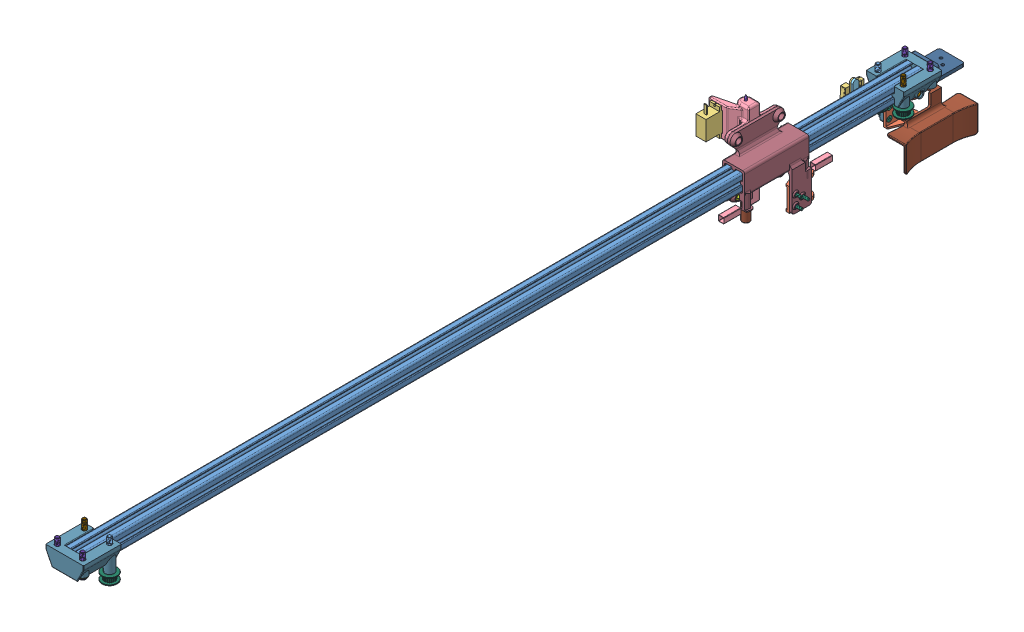
SolidWorks assembly Carriage, configuration Default. Lengths in mm.
Overall size (109.07 129.45 1054.45).
58 component instances, 29 part files, 90 mates.
Components (placement in the parent):
- 5537T237_T-Slotted Framing-1: 5537T237_T-Slotted Framing [5537T237] at origin size (19.99 19.99 1000.12)
- PenHolder-1: PenHolder [Default] at (-13.302 -1.1391 -322.9776) x (0 0 1) z (1 0 0) size (64.55 129.45 48.11)
  - Servo Lever-1: Servo Lever [Default] at (-0.5 -33.948 -30.734) x (0 -0.984808 -0.173648) z (0 -0.173648 0.984808) size (7.3 5 34)
  - SG90 Servo-1: SG90 Servo [Default] at (9.8 -28.448 -30.734) x (0 1 0) z (0 0 1) size (37.7 30.3 12)
  - PenHolder-1: PenHolder [Default] at origin size (63.5 101.91 40.64)
  - Assembly Ink Cartridge Pilot G2-1: Assembly Ink Cartridge Pilot G2 [Default] at (-23.3837 82.6746 -54.1169) x (1 0 0) z (0 -1 0) size (8.33 8.33 120.93)
    - Ink Container Tube-2: Ink Container Tube [Default] at (23.3837 43.9569 29.8776) x (-1 0 0) z (0 1 0) size (6.2 88 6)
    - Ink Container Back Plug-1: Ink Container Back Plug [Default] at (23.3837 43.9569 29.8776) x (1 0 0) z (0 1 0) size (6 4.9 6)
    - Pen Tip Holder-1: Pen Tip Holder [Default] at (23.3837 43.9569 117.8776) x (0.558829 -0.829283 0) z (0.829283 0.558829 0) size (6 18.11 6)
    - Pen Tip-1: Pen Tip [Default] at (23.3837 43.9569 135.6644) x (0.943336 0.33184 0) z (-0.33184 0.943336 0) size (2.59 15.69 2.63)
    - Roller Ball-2: Roller Ball [Default] at (23.3837 43.9569 138.8644) x (0.307657 -0.299861 -0.903012) z (0.951494 0.099481 0.29114) size (0.5 0.5 0.5)
    - Spring-3: Spring [Write] at (23.3837 43.9569 20.2276) x (1 0 0) z (0 -1 0) size (7.26 11.16 7.26)
  - Spring Cap-1: Spring Cap [Default] at (0 19.5395 -10.16) x (0.422618 0 0.906308) z (-0.906308 0 0.422618) size (8.89 53.34 10.92)
  - Pen Lifter-1: Pen Lifter [Default] at (0 -47.625 -10.16) x (-1 0 0) z (0 0 -1) size (8.89 15.4 11.43)
- CarriageSlide2-1: CarriageSlide2 [Default] at (0 0 -322.9776) x (0 1 0) z (0 0 1) size (91.53 37.4 76.2)
- GantryMount-1: GantryMount [Default] at (0 9.8114 -487.5625) x (1 0 0) z (0 0 -1) size (47.54 60.96 45)
- GT2_T2_Pulley_dzino-1: GT2_T2_Pulley_dzino [Výchozí] at (-15 -18.8236 -471.5625) x (-1 0 0) z (0 0 1) size (18 8.5 18)
- GT2_T2_Pulley_dzino-2: GT2_T2_Pulley_dzino [Výchozí] at (15 -10.8236 -471.5625) x (-1 0 0) z (0 0 1) size (18 8.5 18)
- 98269A440_Black-Oxide 18-8 Stainless Steel Washer-1: 98269A440_Black-Oxide 18-8 Stainless Steel Washer [98269A440] at (15 -6.0636 -503.5625) x (0 0 -1) z (0 -1 0) size (10 10 1.1)
- 97763A433_18-8 Stainless Steel Button Head Hex Drive Screws-1: 97763A433_18-8 Stainless Steel Button Head Hex Drive Screws [97763A433] at (15 -9.9136 -503.5625) x (-0.234384 0 -0.972144) z (0 -1 0) size (9.5 9.5 28.3)
- 91239A240_Button Head Hex Drive Screw-1: 91239A240_Button Head Hex Drive Screw [91239A240] at (15 -0.6986 -471.5625) x (0 0 -1) z (0 -1 0) size (9.5 9.5 43.34)
- 98269A440_Black-Oxide 18-8 Stainless Steel Washer-3: 98269A440_Black-Oxide 18-8 Stainless Steel Washer [98269A440] at (-15 -7.1636 -503.5625) x (-0.383049 0 0.923728) z (0 1 0) size (10 10 1.1)
- 97763A433_18-8 Stainless Steel Button Head Hex Drive Screws-2: 97763A433_18-8 Stainless Steel Button Head Hex Drive Screws [97763A433] at (-15 -9.9136 -503.5625) x (-0.129266 0 -0.99161) z (0 -1 0) size (9.5 9.5 28.3)
- 91239A244_Button Head Hex Drive Screw-2: 91239A244_Button Head Hex Drive Screw [91239A244] at (-15 -6.1986 -471.5625) x (0 0 -1) z (0 -1 0) size (9.5 9.5 48.37)
- CableChainEnd-1: CableChainEnd [Default] at (-11.44 -41.1486 -507.5595) x (0 0 1) z (0 1 0) size (33 14.5 27.6)
- 97763A433_18-8 Stainless Steel Button Head Hex Drive Screws-3: 97763A433_18-8 Stainless Steel Button Head Hex Drive Screws [97763A433] at (15 -9.9136 503.5625) x (0.234384 0 -0.972144) z (0 -1 0) size (9.5 9.5 28.3)
- 98269A440_Black-Oxide 18-8 Stainless Steel Washer-4: 98269A440_Black-Oxide 18-8 Stainless Steel Washer [98269A440] at (15 -6.0636 503.5625) x (0 0 -1) z (0 -1 0) size (10 10 1.1)
- 97763A433_18-8 Stainless Steel Button Head Hex Drive Screws-4: 97763A433_18-8 Stainless Steel Button Head Hex Drive Screws [97763A433] at (-15 -9.9136 503.5625) x (0.129266 0 -0.99161) z (0 -1 0) size (9.5 9.5 28.3)
- 98269A440_Black-Oxide 18-8 Stainless Steel Washer-5: 98269A440_Black-Oxide 18-8 Stainless Steel Washer [98269A440] at (-15 -7.1636 503.5625) x (0.383049 0 0.923728) z (0 1 0) size (10 10 1.1)
- GantryMount-3: GantryMount [NoCableCarrier] at (0 9.8114 487.5625) x (-1 0 0) z (0 0 1) size (45 28.63 45)
- CableChainEnd-2: CableChainEnd [Default] at (6.052 -42.484 -363.9276) x (0 0 1) z (0 -1 0) size (33 14.5 27.6)
- LimitSwitch-1: LimitSwitch [Default] at (-14.5667 5.08 -440.6225) x (0 1 0) z (1 0 0) size (26.78 26.12 9.4)
- BeltClip-1: BeltClip [Default] at (-11.6655 -23.2269 -377.4276) size (6.6 6.6 20)
- BeltClip-2: BeltClip [Default] at (11.6655 -23.2269 -377.4276) x (-1 0 0) z (0 0 -1) size (6.6 6.6 20)
- BeltClip-5: BeltClip [Default] at (11.6655 -23.2269 -268.5276) x (-1 0 0) z (0 0 -1) size (6.6 6.6 20)
- BeltClip-6: BeltClip [Default] at (-11.6655 -23.2269 -268.5276) size (6.6 6.6 20)
- SwitchMount-1: SwitchMount [Default] at (-8.1915 0 -451.0925) x (-1 0 0) z (0 0 1) size (12.06 26.78 27.94)
- GT2_T2_Pulley_dzino-7: GT2_T2_Pulley_dzino [Výchozí] at (-15 -10.8236 471.5625) x (-1 0 0) z (0 0 1) size (18 8.5 18)
- GT2_T2_Pulley_dzino-8: GT2_T2_Pulley_dzino [Výchozí] at (15 -18.8236 471.5625) x (-1 0 0) z (0 0 1) size (18 8.5 18)
- 91239A244_Button Head Hex Drive Screw-3: 91239A244_Button Head Hex Drive Screw [91239A244] at (15 -6.1986 471.5625) x (0 0 -1) z (0 -1 0) size (9.5 9.5 48.37)
- 91239A240_Button Head Hex Drive Screw-2: 91239A240_Button Head Hex Drive Screw [91239A240] at (-15 -0.6986 471.5625) x (0 0 -1) z (0 -1 0) size (9.5 9.5 43.34)
- 91294A133_Black-Oxide Alloy Steel Hex Drive Flat Head Screw-1: 91294A133_Black-Oxide Alloy Steel Hex Drive Flat Head Screw [91294A133] at (-15.64 -47.1486 -485.8095) x (0 0 -1) z (1 0 0) size (6 6 14.33)
- 91294A133_Black-Oxide Alloy Steel Hex Drive Flat Head Screw-2: 91294A133_Black-Oxide Alloy Steel Hex Drive Flat Head Screw [91294A133] at (-15.64 -41.1486 -493.8095) x (0 0 -1) z (1 0 0) size (6 6 14.33)
- 91294A133_Black-Oxide Alloy Steel Hex Drive Flat Head Screw-3: 91294A133_Black-Oxide Alloy Steel Hex Drive Flat Head Screw [91294A133] at (-15.64 -35.1486 -485.8095) x (0 0 -1) z (1 0 0) size (6 6 14.33)
- 91294A133_Black-Oxide Alloy Steel Hex Drive Flat Head Screw-4: 91294A133_Black-Oxide Alloy Steel Hex Drive Flat Head Screw [91294A133] at (10.252 -48.484 -342.1776) x (0 0 1) z (-1 0 0) size (6 6 14.33)
- 91294A133_Black-Oxide Alloy Steel Hex Drive Flat Head Screw-5: 91294A133_Black-Oxide Alloy Steel Hex Drive Flat Head Screw [91294A133] at (10.252 -42.484 -350.1776) x (0 0 1) z (-1 0 0) size (6 6 14.33)
- 91294A133_Black-Oxide Alloy Steel Hex Drive Flat Head Screw-6: 91294A133_Black-Oxide Alloy Steel Hex Drive Flat Head Screw [91294A133] at (10.252 -36.484 -342.1776) x (0 0 1) z (-1 0 0) size (6 6 14.33)
- 10-24 Insert-1: 10-24 Insert [Default] at (-9.558 -28.575 -297.5776) x (0 -0.924225 -0.381849) z (-1 0 0) size (7.5 7.5 5.71)
- M3 Threaded Insert-1: M3 Threaded Insert [Default] at (16.167 -48.484 -342.1776) x (0 0 1) z (-1 0 0) size (4.15 4.15 3.16)
- M3 Threaded Insert-2: M3 Threaded Insert [Default] at (-23.46 -47.1486 -485.8095) x (0 0 1) z (-1 0 0) size (4.15 4.15 3.16)
- M5 Threaded Insert-1: M5 Threaded Insert [Default] at (8.89 4.7314 -507.0625) size (6.3 6.3 6)
- M5 Threaded Insert-2: M5 Threaded Insert [Default] at (-8.89 4.7314 -507.0625) size (6.3 6.3 6)
- M5 Threaded Insert-3: M5 Threaded Insert [Default] at (14.3716 -5.6858 -487.5625) x (0 0.398395 0.917214) z (-1 0 0) size (6.3 6.3 6)
- ChainMount-1: ChainMount [Default] at (0 4.7314 -510.0625) x (1 0 0) z (0 0 -1) size (30.16 18.54 34.29)
- M3 Threaded Insert-3: M3 Threaded Insert [Default] at (-3.6513 -6.7546 -523.1125) x (0 0 1) z (0 1 0) size (4.15 4.15 3.16)
- M3 Threaded Insert-4: M3 Threaded Insert [Default] at (-3.6513 -6.7546 -535.1125) x (0 0 1) z (0 1 0) size (4.15 4.15 3.16)
- M3 Threaded Insert-5: M3 Threaded Insert [Default] at (4.3487 -6.7546 -529.1125) x (0 0 1) z (0 1 0) size (4.15 4.15 3.16)
- CarrierSupport-1: CarrierSupport [Default] at (15 -6.0636 -487.5625) x (1 0 0) z (0 0 -1) size (37.26 49.14 86.36)
Mates (geometry in assembly coordinates):
- Coincident1: coordinate: point of 5537T237_T-Slotted Framing-1
- Coincident63: coincident anti-aligned: plane of CarriageSlide2-1 through (0 0 -322.9776) normal (-1 0 0)
- Coincident64: coincident aligned: plane of CarriageSlide2-1 through (0 0 -322.9776) normal (0 1 0)
- Concentric25: concentric anti-aligned: cylinder of PenHolder-1/PenHolder-1 through (-17.5362 28.575 -348.3776) axis (1 0 0) radius 2.54; cone of CarriageSlide2-1 through (-6.317 28.575 -348.3776) axis (-1 0 0)
- Coincident65: coincident anti-aligned: plane of PenHolder-1/PenHolder-1 through (-13.302 -51.9391 -329.9626) normal (1 0 0); plane of CarriageSlide2-1 through (-13.302 -13.302 -284.8776) normal (-1 0 0)
- Coincident66: coincident anti-aligned: plane of 5537T237_T-Slotted Framing-1 through (-1.1334 6.6251 -500.0625) normal (0 0 -1); plane of GantryMount-1 through (8.1516 7.8614 -500.0625) normal (0 0 1)
- Concentric8: concentric anti-aligned: cylinder of GantryMount-1 through (-15 9.8114 -471.5625) axis (0 -1 0) radius 2.754; cylinder of GT2_T2_Pulley_dzino-1 through (-15 -18.8236 -471.5625) axis (0 1 0) radius 4
- Coincident42: coincident anti-aligned: plane of GantryMount-1 through (15 -10.8236 -471.5625) normal (0 -1 0); plane of GT2_T2_Pulley_dzino-2 through (10.5 -10.8236 -471.5625) normal (0 1 0)
- Concentric9: concentric anti-aligned: cylinder of GantryMount-1 through (15 9.8114 -471.5625) axis (0 -1 0) radius 2.754; cylinder of GT2_T2_Pulley_dzino-2 through (15 -10.8236 -471.5625) axis (0 1 0) radius 4
- Coincident46: coincident anti-aligned: plane of GantryMount-1 through (15 -6.0636 -503.5625) normal (0 -1 0); plane of 98269A440_Black-Oxide 18-8 Stainless Steel Washer-1 through (15 -6.0636 -503.5625) normal (0 1 0)
- Concentric12: concentric aligned: cylinder of GantryMount-1 through (15 -6.0636 -503.5625) axis (0 1 0) radius 5.3975; cylinder of 98269A440_Black-Oxide 18-8 Stainless Steel Washer-1 through (15 -7.1636 -503.5625) axis (0 1 0) radius 5
- Concentric26: concentric aligned: cylinder of GantryMount-1 through (15 9.8114 -503.5625) axis (0 -1 0) radius 2.754; cylinder of 97763A433_18-8 Stainless Steel Button Head Hex Drive Screws-1 through (15 -9.9136 -503.5625) axis (0 -1 0) radius 4.75
- Concentric27: concentric aligned: cylinder of GantryMount-1 through (15 9.8114 -471.5625) axis (0 -1 0) radius 2.754; cylinder of 91239A240_Button Head Hex Drive Screw-1 through (15 -22.0736 -471.5625) axis (0 -1 0) radius 4.75
- Coincident52: coincident anti-aligned: plane of GantryMount-1 through (-15 -6.0636 -503.5625) normal (0 -1 0); plane of 98269A440_Black-Oxide 18-8 Stainless Steel Washer-3 through (-15 -6.0636 -503.5625) normal (0 1 0)
- Concentric182: concentric aligned: cylinder of GantryMount-1 through (-15 9.8114 -471.5625) axis (0 -1 0) radius 2.754; cylinder of 91239A244_Button Head Hex Drive Screw-2 through (-15 -30.0736 -471.5625) axis (0 -1 0) radius 4.75
- Coincident68: coincident anti-aligned: plane of GantryMount-1 through (-18.69 9.8114 -487.5625) normal (1 0 0); plane of CableChainEnd-1 through (-18.69 -27.3486 -507.5595) normal (-1 0 0)
- Concentric183: concentric anti-aligned: cylinder of GantryMount-1 through (22.5 -47.1486 -485.8095) axis (-1 0 0) radius 1.7; cylinder of CableChainEnd-1 through (-15.69 -47.1486 -485.8095) axis (1 0 0) radius 1.7
- Parallel5: parallel aligned: plane of GantryMount-1 through (-18.69 -51.1486 -481.5725) normal (0 -1 0); plane of CableChainEnd-1 through (-11.44 -54.9486 -507.5595) normal (0 -1 0)
- Coincident71: coincident anti-aligned: plane of GT2_T2_Pulley_dzino-1 through (-15 -27.3236 -471.5625) normal (0 -1 0); plane of 91239A244_Button Head Hex Drive Screw-2 through (-19.75 -27.3236 -471.5625) normal (0 1 0)
- Coincident72: coincident anti-aligned: plane of GT2_T2_Pulley_dzino-2 through (15 -19.3236 -471.5625) normal (0 -1 0); plane of 91239A240_Button Head Hex Drive Screw-1 through (15 -19.3236 -476.3125) normal (0 1 0)
- Coincident74: coincident anti-aligned: plane of 98269A440_Black-Oxide 18-8 Stainless Steel Washer-1 through (15 -7.1636 -503.5625) normal (0 -1 0); plane of 97763A433_18-8 Stainless Steel Button Head Hex Drive Screws-1 through (10.3823 -7.1636 -502.4492) normal (0 1 0)
- Coincident53: coincident anti-aligned: plane of 98269A440_Black-Oxide 18-8 Stainless Steel Washer-3 through (-15 -7.1636 -503.5625) normal (0 -1 0); plane of 97763A433_18-8 Stainless Steel Button Head Hex Drive Screws-2 through (-19.7101 -7.1636 -502.9485) normal (0 1 0)
- Concentric184: concentric aligned: cylinder of GantryMount-1 through (-15 9.8114 -503.5625) axis (0 -1 0) radius 2.754; cylinder of 98269A440_Black-Oxide 18-8 Stainless Steel Washer-3 through (-15 -6.0636 -503.5625) axis (0 -1 0) radius 5
- Concentric185: concentric aligned: cylinder of GantryMount-1 through (-15 9.8114 -503.5625) axis (0 -1 0) radius 2.754; cylinder of 97763A433_18-8 Stainless Steel Button Head Hex Drive Screws-2 through (-15 -9.9136 -503.5625) axis (0 -1 0) radius 4.75
- Parallel6: parallel aligned: plane of 5537T237_T-Slotted Framing-1 through (-7.9883 -9.9949 500.0625) normal (0 -1 0); plane of GantryMount-1 through (15 -10.1886 -510.0625) normal (0 -1 0)
- Coincident80: coincident aligned: plane of CarriageSlide2-1 through (13.302 -13.302 -284.8776) normal (1 0 0); plane of CableChainEnd-2 through (13.302 -56.284 -363.9276) normal (1 0 0)
- Coincident81: coincident aligned: plane of CarriageSlide2-1 through (0 0 -361.0776) normal (0 0 -1); plane of CableChainEnd-2 through (-1.198 -32.484 -361.0776) normal (0 0 -1)
- Coincident84: coincident aligned: plane of CarriageSlide2-1 through (-12.2707 -26.2729 -356.3151) normal (0 1 0); plane of BeltClip-1 through (-14.4575 -26.2729 -367.4276) normal (0 1 0)
- Distance1: distance = 6.35 mm anti-aligned: plane of BeltClip-1 through (-14.4575 -20.4349 -367.4276) normal (0 0 1); plane of CarriageSlide2-1 through (0 0 -361.0776) normal (0 0 -1)
- Distance2: distance = 1.27 mm anti-aligned: plane of CarriageSlide2-1 through (-9.8895 3.6806 -361.0776) normal (1 0 0); plane of BeltClip-1 through (-8.6195 -20.4349 -367.4276) normal (-1 0 0)
- Coincident90: coincident anti-aligned: plane of CarriageSlide2-1 through (0 0 -322.9776) normal (0 1 0); plane of SwitchMount-1 through (-8.1915 0 -451.0925) normal (0 -1 0)
- Coincident91: coincident anti-aligned: plane of GantryMount-1 through (0 9.8114 -465.0625) normal (0 0 1); plane of SwitchMount-1 through (-8.1915 0 -465.0625) normal (0 0 -1)
- Coincident92: coincident anti-aligned: plane of 5537T237_T-Slotted Framing-1 through (-8.1915 4.9149 500.0625) normal (1 0 0); plane of SwitchMount-1 through (-8.1915 -2.3749 -437.1225) normal (-1 0 0)
- Concentric187: concentric anti-aligned: cylinder of LimitSwitch-1 through (-12.9667 -4.81 -440.6225) axis (-1 0 0) radius 1.75; cylinder of SwitchMount-1 through (-14.9987 -4.81 -440.6225) axis (1 0 0) radius 1.6
- Coincident93: coincident anti-aligned: plane of LimitSwitch-1 through (-12.9667 -4.81 -440.6225) normal (1 0 0); plane of SwitchMount-1 through (-12.9667 14.97 -440.6225) normal (-1 0 0)
- Perpendicular1: perpendicular: plane of LimitSwitch-1 through (-20.2967 10.08 -447.7225) normal (0 0 1); plane of SwitchMount-1 through (-8.1915 2.3749 -437.1225) normal (0 1 0)
- Coincident94: coincident anti-aligned: plane of GantryMount-1 through (-15 -18.8236 -471.5625) normal (0 -1 0); plane of GT2_T2_Pulley_dzino-1 through (-15 -18.8236 -471.5625) normal (0 1 0)
- Concentric188: concentric aligned: cylinder of GantryMount-3 through (15 9.8114 471.5625) axis (0 -1 0) radius 2.754; cylinder of GT2_T2_Pulley_dzino-8 through (15 -25.8236 471.5625) axis (0 -1 0) radius 2.5
- Coincident95: coincident anti-aligned: plane of GantryMount-3 through (15 -18.8236 471.5625) normal (0 -1 0); plane of GT2_T2_Pulley_dzino-8 through (15 -18.8236 471.5625) normal (0 1 0)
- Concentric189: concentric aligned: cylinder of GantryMount-3 through (-15 9.8114 471.5625) axis (0 -1 0) radius 2.754; cylinder of GT2_T2_Pulley_dzino-7 through (-15 -17.8236 471.5625) axis (0 -1 0) radius 2.5
- Coincident96: coincident anti-aligned: plane of GantryMount-3 through (-15 -10.8236 471.5625) normal (0 -1 0); plane of GT2_T2_Pulley_dzino-7 through (-15 -10.8236 471.5625) normal (0 1 0)
- Parallel7: parallel anti-aligned: plane of 91239A244_Button Head Hex Drive Screw-2 through (-15 -6.1986 -471.5625) normal (0 0 -1)
- Parallel8: parallel aligned: plane of GT2_T2_Pulley_dzino-1 through (-15 -18.8236 -471.5625) normal (0 0 1)
- Parallel9: parallel aligned: plane of GT2_T2_Pulley_dzino-2 through (15 -10.8236 -471.5625) normal (0 0 1)
- Parallel10: parallel aligned: plane of GT2_T2_Pulley_dzino-7 through (-15 -10.8236 471.5625) normal (0 0 1)
- Parallel11: parallel aligned: plane of GT2_T2_Pulley_dzino-8 through (15 -18.8236 471.5625) normal (0 0 1)
- Concentric197: concentric aligned: cylinder of GantryMount-3 through (15 9.8114 471.5625) axis (0 -1 0) radius 2.754; cylinder of 91239A244_Button Head Hex Drive Screw-3 through (15 -30.0736 471.5625) axis (0 -1 0) radius 2.5
- Coincident103: coincident anti-aligned: plane of GT2_T2_Pulley_dzino-8 through (15 -27.3236 471.5625) normal (0 -1 0); plane of 91239A244_Button Head Hex Drive Screw-3 through (10.25 -27.3236 471.5625) normal (0 1 0)
- Concentric198: concentric aligned: cylinder of GantryMount-3 through (-15 9.8114 471.5625) axis (0 -1 0) radius 2.754; cylinder of 91239A240_Button Head Hex Drive Screw-2 through (-15 -22.0736 471.5625) axis (0 -1 0) radius 2.5
- Coincident104: coincident anti-aligned: plane of GT2_T2_Pulley_dzino-7 through (-15 -19.3236 471.5625) normal (0 -1 0); plane of 91239A240_Button Head Hex Drive Screw-2 through (-15 -19.3236 466.8125) normal (0 1 0)
- Coincident105: coincident aligned: cone of CableChainEnd-1 through (-15.69 -47.1486 -485.8095) axis (-1 0 0); cone of 91294A133_Black-Oxide Alloy Steel Hex Drive Flat Head Screw-1 through (-17.34 -47.1486 -485.8095) axis (-1 0 0)
- Parallel12: parallel anti-aligned: plane of CableChainEnd-1 through (-11.44 -54.9486 -507.5595) normal (0 -1 0); plane of 91294A133_Black-Oxide Alloy Steel Hex Drive Flat Head Screw-1 through (-15.64 -47.1486 -485.8095) normal (0 1 0)
- Coincident107: coincident aligned: cone of CableChainEnd-1 through (-15.69 -41.1486 -493.8095) axis (-1 0 0); cone of 91294A133_Black-Oxide Alloy Steel Hex Drive Flat Head Screw-2 through (-17.34 -41.1486 -493.8095) axis (-1 0 0)
- Parallel13: parallel anti-aligned: plane of CableChainEnd-1 through (-11.44 -54.9486 -507.5595) normal (0 -1 0); plane of 91294A133_Black-Oxide Alloy Steel Hex Drive Flat Head Screw-2 through (-15.64 -41.1486 -493.8095) normal (0 1 0)
- Coincident109: coincident aligned: cone of CableChainEnd-1 through (-15.69 -35.1486 -485.8095) axis (-1 0 0); cone of 91294A133_Black-Oxide Alloy Steel Hex Drive Flat Head Screw-3 through (-17.34 -35.1486 -485.8095) axis (-1 0 0)
- Parallel14: parallel anti-aligned: plane of CableChainEnd-1 through (-11.44 -54.9486 -507.5595) normal (0 -1 0); plane of 91294A133_Black-Oxide Alloy Steel Hex Drive Flat Head Screw-3 through (-15.64 -35.1486 -485.8095) normal (0 1 0)
- Coincident111: coincident aligned: cone of CableChainEnd-2 through (10.302 -48.484 -342.1776) axis (1 0 0); cone of 91294A133_Black-Oxide Alloy Steel Hex Drive Flat Head Screw-4 through (11.952 -48.484 -342.1776) axis (1 0 0)
- Parallel15: parallel anti-aligned: plane of CableChainEnd-2 through (6.052 -56.284 -363.9276) normal (0 -1 0); plane of 91294A133_Black-Oxide Alloy Steel Hex Drive Flat Head Screw-4 through (10.252 -48.484 -342.1776) normal (0 1 0)
- Coincident113: coincident aligned: cone of CableChainEnd-2 through (10.302 -42.484 -350.1776) axis (1 0 0); cone of 91294A133_Black-Oxide Alloy Steel Hex Drive Flat Head Screw-5 through (11.952 -42.484 -350.1776) axis (1 0 0)
- Parallel16: parallel anti-aligned: plane of CableChainEnd-2 through (6.052 -56.284 -363.9276) normal (0 -1 0); plane of 91294A133_Black-Oxide Alloy Steel Hex Drive Flat Head Screw-5 through (10.252 -42.484 -350.1776) normal (0 1 0)
- Coincident115: coincident aligned: cone of CableChainEnd-2 through (10.302 -36.484 -342.1776) axis (1 0 0); cone of 91294A133_Black-Oxide Alloy Steel Hex Drive Flat Head Screw-6 through (11.952 -36.484 -342.1776) axis (1 0 0)
- Parallel17: parallel anti-aligned: plane of CableChainEnd-2 through (6.052 -56.284 -363.9276) normal (0 -1 0); plane of 91294A133_Black-Oxide Alloy Steel Hex Drive Flat Head Screw-6 through (10.252 -36.484 -342.1776) normal (0 1 0)
- Concentric199: concentric anti-aligned: cylinder of CarriageSlide2-1 through (-16.558 -42.484 -350.1776) axis (1 0 0) radius 1.7; cylinder of CableChainEnd-2 through (10.302 -42.484 -350.1776) axis (-1 0 0) radius 1.7
- Coincident117: coincident aligned: plane of CarriageSlide2-1 through (16.477 -56.284 -361.0776) normal (0 -1 0); plane of CableChainEnd-2 through (6.052 -56.284 -363.9276) normal (0 -1 0)
- Concentric200: concentric anti-aligned: cone of CarriageSlide2-1 through (-6.317 -28.575 -297.5776) axis (-1 0 0); cylinder of 10-24 Insert-1 through (-12.413 -28.575 -297.5776) axis (1 0 0) radius 3.75
- Coincident119: coincident anti-aligned: plane of CarriageSlide2-1 through (-12.413 -28.575 -297.5776) normal (1 0 0); plane of 10-24 Insert-1 through (-12.413 -28.575 -297.5776) normal (-1 0 0)
- Concentric201: concentric aligned: cone of CarriageSlide2-1 through (17.747 -48.484 -342.1776) axis (-1 0 0); cylinder of M3 Threaded Insert-1 through (14.587 -48.484 -342.1776) axis (-1 0 0) radius 1.25
- Coincident120: coincident aligned: plane of CarriageSlide2-1 through (17.747 -48.484 -342.1776) normal (1 0 0); plane of M3 Threaded Insert-1 through (17.747 -48.484 -342.1776) normal (1 0 0)
- Coincident121: coincident aligned: plane of GantryMount-1 through (-25.04 -47.1486 -485.8095) normal (-1 0 0); plane of M3 Threaded Insert-2 through (-25.04 -47.1486 -485.8095) normal (-1 0 0)
- Concentric202: concentric aligned: cone of GantryMount-1 through (-25.04 -47.1486 -485.8095) axis (1 0 0); cylinder of M3 Threaded Insert-2 through (-25.04 -47.1486 -485.8095) axis (1 0 0) radius 1.81
- Coincident122: coincident anti-aligned: plane of 5537T237_T-Slotted Framing-1 through (-8.4963 2.5019 500.0625) normal (0 -1 0); plane of GantryMount-1 through (-10.1016 2.5019 -459.5673) normal (0 1 0)
- Coincident123: coincident aligned: plane of 5537T237_T-Slotted Framing-1 through (0 0 0) normal (1 0 0); plane of GantryMount-1 through (0 9.8114 -487.5625) normal (1 0 0)
- Coincident124: coincident aligned: plane of GantryMount-1 through (0 9.8114 -510.0625) normal (0 0 -1); plane of M5 Threaded Insert-1 through (8.89 4.7314 -510.0625) normal (0 0 -1)
- Coincident125: coincident aligned: plane of GantryMount-1 through (0 9.8114 -510.0625) normal (0 0 -1); plane of M5 Threaded Insert-2 through (-8.89 4.7314 -510.0625) normal (0 0 -1)
- Concentric203: concentric aligned: cone of GantryMount-1 through (-8.89 4.7314 -510.0625) axis (0 0 1); cylinder of M5 Threaded Insert-2 through (-8.89 4.7314 -504.0625) axis (0 0 1) radius 2.1
- Concentric204: concentric aligned: cone of GantryMount-1 through (8.89 4.7314 -510.0625) axis (0 0 1); cylinder of M5 Threaded Insert-1 through (8.89 4.7314 -504.0625) axis (0 0 1) radius 2.1
- Concentric205: concentric aligned: cone of GantryMount-1 through (11.3716 -5.6858 -487.5625) axis (-1 0 0); cylinder of M5 Threaded Insert-3 through (11.3716 -5.6858 -487.5625) axis (-1 0 0) radius 2.1
- Coincident126: coincident anti-aligned: plane of GantryMount-1 through (11.3716 -5.6858 -487.5625) normal (1 0 0); plane of M5 Threaded Insert-3 through (11.3716 -5.6858 -487.5625) normal (-1 0 0)
- Coincident137: coincident anti-aligned: plane of GantryMount-1 through (0 9.8114 -510.0625) normal (0 0 -1); plane of ChainMount-1 through (0 4.7314 -510.0625) normal (0 0 1)
- Parallel18: parallel anti-aligned: plane of GantryMount-1 through (15 -10.1886 -510.0625) normal (0 -1 0); plane of ChainMount-1 through (15.0812 10.0654 -513.8725) normal (0 1 0)
- Concentric206: concentric aligned: cone of ChainMount-1 through (-3.6513 -8.4766 -523.1125) axis (0 1 0); cylinder of M3 Threaded Insert-3 through (-3.6513 -5.1746 -523.1125) axis (0 1 0) radius 1.25
- Coincident138: coincident anti-aligned: plane of ChainMount-1 through (-3.6513 -5.1746 -523.1125) normal (0 -1 0); plane of M3 Threaded Insert-3 through (-3.6513 -5.1746 -523.1125) normal (0 1 0)
- Coincident139: coincident anti-aligned: plane of ChainMount-1 through (-3.6513 -5.1746 -535.1125) normal (0 -1 0); plane of M3 Threaded Insert-4 through (-3.6513 -5.1746 -535.1125) normal (0 1 0)
- Concentric207: concentric aligned: cone of ChainMount-1 through (-3.6513 -8.4766 -535.1125) axis (0 1 0); cylinder of M3 Threaded Insert-4 through (-3.6513 -5.1746 -535.1125) axis (0 1 0) radius 1.25
- Coincident140: coincident anti-aligned: plane of ChainMount-1 through (4.3487 -5.1746 -529.1125) normal (0 -1 0); plane of M3 Threaded Insert-5 through (4.3487 -5.1746 -529.1125) normal (0 1 0)
- Concentric208: concentric aligned: cone of ChainMount-1 through (4.3487 -8.4766 -529.1125) axis (0 1 0); cylinder of M3 Threaded Insert-5 through (4.3487 -5.1746 -529.1125) axis (0 1 0) radius 1.25
- Concentric209: concentric anti-aligned: cylinder of M5 Threaded Insert-1 through (8.89 4.7314 -504.0625) axis (0 0 1) radius 2.1; cylinder of ChainMount-1 through (8.89 4.7314 -513.8725) axis (0 0 -1) radius 2.75
- Concentric210: concentric aligned: cylinder of 98269A440_Black-Oxide 18-8 Stainless Steel Washer-1 through (15 -7.1636 -503.5625) axis (0 1 0) radius 5; cylinder of CarrierSupport-1 through (15 -8.0956 -503.5625) axis (0 1 0) radius 4.6
- Parallel19: parallel anti-aligned: plane of GantryMount-1 through (0 9.8114 -510.0625) normal (0 0 -1); plane of CarrierSupport-1 through (15 -8.0956 -498.9625) normal (0 0 1)
- Coincident143: coincident anti-aligned: plane of GantryMount-1 through (15 -6.0636 -503.5625) normal (0 -1 0); plane of CarrierSupport-1 through (15 -6.0636 -503.5625) normal (0 1 0)
